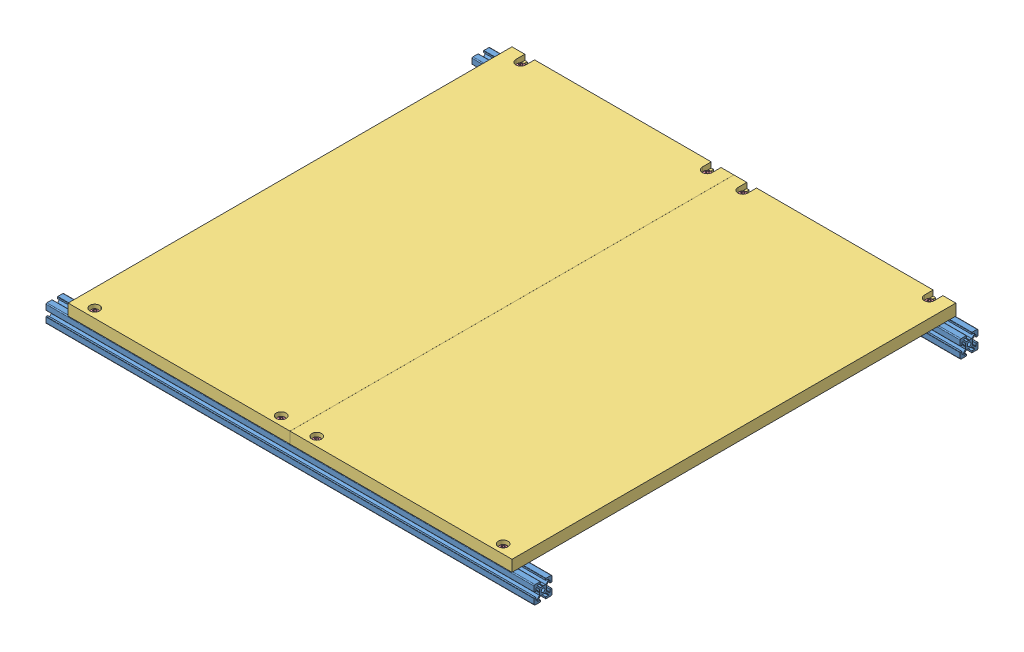
SolidWorks assembly S2_Work_Area_500, configuration Default. Lengths in mm.
Overall size (550 32.7 500).
29 component instances, 5 part files, 65 mates.
Components (placement in the parent):
- 26049-01_550-1: 26049-01_550 [Default] at (-284.2078 -90.7646 -9.7589) x (0 0 1) z (-1 0 0) size (20 20 550)
- 26049-01_550-2: 26049-01_550 [Default] at (-284.2078 -90.7646 -489.7589) x (0 0 1) z (-1 0 0) size (20 20 550)
- 26016-01-1: 26016-01 [Default] at (670.7922 -82.7646 -9.7589) x (0 0 -1) z (-1 0 0) size (10 1.6 15)
- 26016-01-2: 26016-01 [Default] at (670.7922 -82.7646 -489.7589) x (0 0 -1) z (-1 0 0) size (10 1.6 15)
- 26016-01-3: 26016-01 [Default] at (460.7922 -82.7646 -9.7589) x (0 0 -1) z (-1 0 0) size (10 1.6 15)
- 26016-01-4: 26016-01 [Default] at (460.7922 -82.7646 -489.7589) x (0 0 -1) z (-1 0 0) size (10 1.6 15)
- 26016-01-6: 26016-01 [Default] at (420.7422 -82.7646 -489.7589) x (0 0 -1) z (-1 0 0) size (10 1.6 15)
- 26016-01-5: 26016-01 [Default] at (420.7422 -82.7646 -9.7589) x (0 0 -1) z (-1 0 0) size (10 1.6 15)
- 26016-01-7: 26016-01 [Default] at (210.7422 -82.7646 -9.7589) x (0 0 -1) z (-1 0 0) size (10 1.6 15)
- 26016-01-8: 26016-01 [Default] at (210.7422 -82.7646 -489.7589) x (0 0 -1) z (-1 0 0) size (10 1.6 15)
- two_part_wastebaord_500-1: two_part_wastebaord_500 [Default] at (315.7422 -80.7646 -249.7589) x (1 0 0) z (0 1 0) size (250 500 12.7)
- two_part_wastebaord_500-2: two_part_wastebaord_500 [Default] at (565.7922 -80.7646 -249.7589) x (1 0 0) z (0 1 0) size (250 500 12.7)
- 25286-02-1: 25286-02 [Default] at (670.7922 -85.1646 -9.7589) x (0.431918 0 -0.901913) z (0 -1 0) size (9.5 9.5 14.91)
- 25287-02-1: 25287-02 [Default] at (670.7922 -74.0646 -9.7589) x (0.969299 0 -0.245884) z (0 -1 0) size (10 10 0.9)
- 25286-02-2: 25286-02 [Default] at (670.7922 -85.1646 -489.7589) x (1 0 0) z (0 -1 0) size (9.5 9.5 14.91)
- 25287-02-2: 25287-02 [Default] at (670.7922 -73.1646 -489.7589) x (1 0 0) z (0 1 0) size (10 10 0.9)
- 25286-02-3: 25286-02 [Default] at (460.7922 -85.1646 -9.7589) x (1 0 0) z (0 -1 0) size (9.5 9.5 14.91)
- 25287-02-3: 25287-02 [Default] at (460.7922 -73.1646 -9.7589) x (-1 0 0) z (0 1 0) size (10 10 0.9)
- 25286-02-4: 25286-02 [Default] at (460.7922 -85.1646 -489.7589) x (1 0 0) z (0 -1 0) size (9.5 9.5 14.91)
- 25287-02-4: 25287-02 [Default] at (460.7922 -73.1646 -489.7589) x (1 0 0) z (0 1 0) size (10 10 0.9)
- 25286-02-5: 25286-02 [Default] at (420.7422 -85.1646 -9.7589) x (1 0 0) z (0 -1 0) size (9.5 9.5 14.91)
- 25287-02-5: 25287-02 [Default] at (420.7422 -74.0646 -9.7589) x (0.837169 0 0.546944) z (0 -1 0) size (10 10 0.9)
- 25286-02-6: 25286-02 [Default] at (420.7422 -85.1646 -489.7589) x (1 0 0) z (0 -1 0) size (9.5 9.5 14.91)
- 25287-02-6: 25287-02 [Default] at (420.7422 -73.1646 -489.7589) x (1 0 0) z (0 1 0) size (10 10 0.9)
- 25286-02-7: 25286-02 [Default] at (210.7422 -85.1646 -9.7589) x (1 0 0) z (0 -1 0) size (9.5 9.5 14.91)
- 25287-02-7: 25287-02 [Default] at (210.7422 -73.1646 -9.7589) x (0.99999 0 -0.004532) z (0 1 0) size (10 10 0.9)
- 25286-02-8: 25286-02 [Default] at (210.7422 -85.1646 -489.7589) x (1 0 0) z (0 -1 0) size (9.5 9.5 14.91)
- 25287-02-8: 25287-02 [Default] at (210.7422 -73.1646 -489.7589) x (1 0 0) z (0 1 0) size (10 10 0.9)
- 25286-02-9: 25286-02 [Default] at (355.5212 -66.0869 -9.4798) x (1 0 0) z (0 -1 0) size (9.5 9.5 14.91) (suppressed, hidden)
Mates (geometry in assembly coordinates):
- Coincident1: coincident aligned: plane of 26049-01_550-1 through (-284.2078 -80.7646 -13.0589) normal (0 1 0); plane of 26049-01_550-2 through (-284.2078 -80.7646 -480.7589) normal (0 1 0)
- Coincident3: coincident aligned: plane of 26049-01_550-1 through (-284.2078 -90.7646 -9.7589) normal (-1 0 0); plane of 26049-01_550-2 through (-284.2078 -90.7646 -489.7589) normal (-1 0 0)
- Coincident4: coincident anti-aligned: plane of 26049-01_550-1 through (-284.2078 -80.7646 -0.7589) normal (0 1 0); plane of two_part_wastebaord_500-1 through (315.7422 -80.7646 -249.7589) normal (0 -1 0)
- Coincident6: coincident anti-aligned: plane of 26049-01_550-2 through (-284.2078 -82.7646 -486.7589) normal (0 -1 0); plane of 26016-01-8 through (210.7422 -82.7646 -489.7589) normal (0 1 0)
- Coincident7: coincident anti-aligned: plane of 26049-01_550-1 through (-284.2078 -90.7646 -9.7589) normal (0 0 1); plane of 26016-01-7
- Coincident8: coincident anti-aligned: plane of 26049-01_550-1 through (-284.2078 -82.7646 -6.7589) normal (0 -1 0); plane of 26016-01-7 through (210.7422 -82.7646 -9.7589) normal (0 1 0)
- Coincident9: coincident anti-aligned: plane of 26049-01_550-1 through (-284.2078 -82.7646 -6.7589) normal (0 -1 0); plane of 26016-01-5 through (420.7422 -82.7646 -9.7589) normal (0 1 0)
- Coincident10: coincident anti-aligned: plane of 26049-01_550-1 through (-284.2078 -82.7646 -6.7589) normal (0 -1 0); plane of 26016-01-3 through (460.7922 -82.7646 -9.7589) normal (0 1 0)
- Coincident11: coincident anti-aligned: plane of 26049-01_550-1 through (-284.2078 -82.7646 -6.7589) normal (0 -1 0); plane of 26016-01-1 through (670.7922 -82.7646 -9.7589) normal (0 1 0)
- Coincident12: coincident anti-aligned: plane of 26049-01_550-2 through (-284.2078 -82.7646 -486.7589) normal (0 -1 0); plane of 26016-01-8 through (210.7422 -82.7646 -489.7589) normal (0 1 0)
- Coincident13: coincident anti-aligned: plane of 26049-01_550-2 through (-284.2078 -82.7646 -486.7589) normal (0 -1 0); plane of 26016-01-6 through (420.7422 -82.7646 -489.7589) normal (0 1 0)
- Coincident14: coincident anti-aligned: plane of 26049-01_550-2 through (-284.2078 -82.7646 -486.7589) normal (0 -1 0); plane of 26016-01-4 through (460.7922 -82.7646 -489.7589) normal (0 1 0)
- Coincident15: coincident anti-aligned: plane of 26049-01_550-2 through (-284.2078 -82.7646 -486.7589) normal (0 -1 0); plane of 26016-01-2 through (670.7922 -82.7646 -489.7589) normal (0 1 0)
- Coincident16: coincident anti-aligned: plane of 26049-01_550-2 through (-284.2078 -90.7646 -489.7589) normal (0 0 1); plane of 26016-01-2
- Coincident17: coincident anti-aligned: plane of 26049-01_550-2 through (-284.2078 -90.7646 -489.7589) normal (0 0 1); plane of 26016-01-4
- Coincident18: coincident anti-aligned: plane of 26049-01_550-2 through (-284.2078 -90.7646 -489.7589) normal (0 0 1); plane of 26016-01-6
- Coincident19: coincident anti-aligned: plane of 26049-01_550-2 through (-284.2078 -90.7646 -489.7589) normal (0 0 1); plane of 26016-01-8
- Coincident20: coincident anti-aligned: plane of 26049-01_550-2 through (-284.2078 -80.7646 -493.0589) normal (0 1 0); plane of two_part_wastebaord_500-1 through (315.7422 -80.7646 -249.7589) normal (0 -1 0)
- Concentric1: concentric: cylinder of 26016-01-8 through (210.7422 -82.7646 -489.7589) axis (0 -1 0) radius 2.5; cylinder of two_part_wastebaord_500-1 through (210.7422 -627.2258 -489.7589) axis (0 1 0) radius 2.75
- Concentric2: concentric: cylinder of 26016-01-6 through (420.7422 -82.7646 -489.7589) axis (0 -1 0) radius 2.5; cylinder of two_part_wastebaord_500-1 through (420.7422 -627.2258 -489.7589) axis (0 1 0) radius 2.75
- Concentric3: concentric: cylinder of 26016-01-4 through (460.7922 -82.7646 -489.7589) axis (0 -1 0) radius 2.5; cylinder of two_part_wastebaord_500-2 through (460.7922 -627.2258 -489.7589) axis (0 1 0) radius 2.75
- Concentric4: concentric anti-aligned: cylinder of 26016-01-2 through (670.7922 -82.7646 -489.7589) axis (0 -1 0) radius 2.5; cylinder of two_part_wastebaord_500-2 through (670.7922 -627.2258 -489.7589) axis (0 1 0) radius 2.75
- Concentric6: concentric anti-aligned: cylinder of 26016-01-7 through (210.7422 -82.7646 -9.7589) axis (0 -1 0) radius 2.5; cylinder of two_part_wastebaord_500-1 through (210.7422 -627.2258 -9.7589) axis (0 1 0) radius 2.75
- Concentric7: concentric anti-aligned: cylinder of 26016-01-5 through (420.7422 -82.7646 -9.7589) axis (0 -1 0) radius 2.5; cylinder of two_part_wastebaord_500-1 through (420.7422 -627.2258 -9.7589) axis (0 1 0) radius 2.75
- Concentric8: concentric: cylinder of 26016-01-3 through (460.7922 -82.7646 -9.7589) axis (0 -1 0) radius 2.5; cylinder of two_part_wastebaord_500-2 through (460.7922 -627.2258 -9.7589) axis (0 1 0) radius 2.75
- Concentric9: concentric anti-aligned: cylinder of 26016-01-1 through (670.7922 -82.7646 -9.7589) axis (0 -1 0) radius 2.5; cylinder of two_part_wastebaord_500-2 through (670.7922 -627.2258 -9.7589) axis (0 1 0) radius 2.75
- Distance2: distance = 0.05 mm: plane of two_part_wastebaord_500-1 through (440.7422 -80.7646 0.2411) normal (1 0 0); plane of two_part_wastebaord_500-2 through (440.7922 -80.7646 -499.7589) normal (-1 0 0)
- Concentric10: concentric anti-aligned: cylinder of 26016-01-2 through (670.7922 -82.7646 -489.7589) axis (0 -1 0) radius 2.5; cylinder of 25287-02-2 through (670.7922 -74.0646 -489.7589) axis (0 1 0) radius 2.65
- Coincident22: coincident: plane of two_part_wastebaord_500-2 through (670.7922 -74.0646 -489.7589) normal (0 1 0); plane of 25287-02-2 through (670.7922 -74.0646 -489.7589) normal (0 -1 0)
- Concentric11: concentric anti-aligned: cylinder of 26016-01-4 through (460.7922 -82.7646 -489.7589) axis (0 -1 0) radius 2.5; cylinder of 25287-02-4 through (460.7922 -74.0646 -489.7589) axis (0 1 0) radius 2.65
- Coincident23: coincident anti-aligned: plane of two_part_wastebaord_500-2 through (460.7922 -74.0646 -489.7589) normal (0 1 0); plane of 25287-02-4 through (460.7922 -74.0646 -489.7589) normal (0 -1 0)
- Coincident24: coincident anti-aligned: plane of two_part_wastebaord_500-1 through (420.7422 -74.0646 -489.7589) normal (0 1 0); plane of 25287-02-6 through (420.7422 -74.0646 -489.7589) normal (0 -1 0)
- Concentric12: concentric anti-aligned: cylinder of 26016-01-6 through (420.7422 -82.7646 -489.7589) axis (0 -1 0) radius 2.5; cylinder of 25287-02-6 through (420.7422 -74.0646 -489.7589) axis (0 1 0) radius 2.65
- Coincident25: coincident anti-aligned: plane of two_part_wastebaord_500-1 through (210.7422 -74.0646 -489.7589) normal (0 1 0); plane of 25287-02-8 through (210.7422 -74.0646 -489.7589) normal (0 -1 0)
- Concentric13: concentric anti-aligned: cylinder of 26016-01-8 through (210.7422 -82.7646 -489.7589) axis (0 -1 0) radius 2.5; cylinder of 25287-02-8 through (210.7422 -74.0646 -489.7589) axis (0 1 0) radius 2.65
- Concentric14: concentric anti-aligned: cylinder of 26016-01-7 through (210.7422 -82.7646 -9.7589) axis (0 -1 0) radius 2.5; cylinder of 25287-02-7 through (210.7422 -74.0646 -9.7589) axis (0 1 0) radius 2.65
- Coincident26: coincident anti-aligned: plane of two_part_wastebaord_500-1 through (210.7422 -74.0646 -9.7589) normal (0 1 0); plane of 25287-02-7 through (210.7422 -74.0646 -9.7589) normal (0 -1 0)
- Concentric15: concentric aligned: cylinder of 26016-01-5 through (420.7422 -82.7646 -9.7589) axis (0 -1 0) radius 2.5; cylinder of 25287-02-5 through (420.7422 -73.1646 -9.7589) axis (0 -1 0) radius 2.65
- Coincident27: coincident anti-aligned: plane of two_part_wastebaord_500-1 through (420.7422 -74.0646 -9.7589) normal (0 1 0); plane of 25287-02-5 through (420.7422 -74.0646 -9.7589) normal (0 -1 0)
- Concentric16: concentric anti-aligned: cylinder of 26016-01-3 through (460.7922 -82.7646 -9.7589) axis (0 -1 0) radius 2.5; cylinder of 25287-02-3 through (460.7922 -74.0646 -9.7589) axis (0 1 0) radius 2.65
- Coincident28: coincident anti-aligned: plane of two_part_wastebaord_500-2 through (460.7922 -74.0646 -9.7589) normal (0 1 0); plane of 25287-02-3 through (460.7922 -74.0646 -9.7589) normal (0 -1 0)
- Concentric17: concentric aligned: cylinder of 26016-01-1 through (670.7922 -82.7646 -9.7589) axis (0 -1 0) radius 2.5; cylinder of 25287-02-1 through (670.7922 -73.1646 -9.7589) axis (0 -1 0) radius 2.65
- Coincident29: coincident anti-aligned: plane of two_part_wastebaord_500-2 through (670.7922 -74.0646 -9.7589) normal (0 1 0); plane of 25287-02-1 through (670.7922 -74.0646 -9.7589) normal (0 -1 0)
- Concentric18: concentric aligned: cylinder of 26016-01-2 through (670.7922 -82.7646 -489.7589) axis (0 -1 0) radius 2.5; cylinder of 25286-02-2 through (670.7922 -70.4146 -489.7589) axis (0 -1 0) radius 4.75
- Coincident30: coincident anti-aligned: plane of 25286-02-2 through (670.7922 -73.1646 -489.7589) normal (0 -1 0); plane of 25287-02-2 through (670.7922 -73.1646 -489.7589) normal (0 1 0)
- Concentric19: concentric aligned: cylinder of 26016-01-4 through (460.7922 -82.7646 -489.7589) axis (0 -1 0) radius 2.5; cylinder of 25286-02-4 through (460.7922 -70.4146 -489.7589) axis (0 -1 0) radius 4.75
- Coincident31: coincident anti-aligned: plane of 25286-02-4 through (460.7922 -73.1646 -489.7589) normal (0 -1 0); plane of 25287-02-4 through (460.7922 -73.1646 -489.7589) normal (0 1 0)
- Concentric20: concentric aligned: cylinder of 26016-01-6 through (420.7422 -82.7646 -489.7589) axis (0 -1 0) radius 2.5; cylinder of 25286-02-6 through (420.7422 -70.4146 -489.7589) axis (0 -1 0) radius 4.75
- Coincident32: coincident anti-aligned: plane of 25286-02-6 through (420.7422 -73.1646 -489.7589) normal (0 -1 0); plane of 25287-02-6 through (420.7422 -73.1646 -489.7589) normal (0 1 0)
- Concentric21: concentric aligned: cylinder of 26016-01-8 through (210.7422 -82.7646 -489.7589) axis (0 -1 0) radius 2.5; cylinder of 25286-02-8 through (210.7422 -70.4146 -489.7589) axis (0 -1 0) radius 4.75
- Coincident33: coincident anti-aligned: plane of 25286-02-8 through (210.7422 -73.1646 -489.7589) normal (0 -1 0); plane of 25287-02-8 through (210.7422 -73.1646 -489.7589) normal (0 1 0)
- Concentric22: concentric: cylinder of 26016-01-7 through (210.7422 -82.7646 -9.7589) axis (0 -1 0) radius 2.5; cylinder of 25286-02-7 through (210.7422 -70.4146 -9.7589) axis (0 -1 0) radius 4.75
- Coincident34: coincident anti-aligned: plane of 25286-02-7 through (210.7422 -73.1646 -9.7589) normal (0 -1 0); plane of 25287-02-7 through (210.7422 -73.1646 -9.7589) normal (0 1 0)
- Concentric23: concentric aligned: cylinder of 25286-02-5 through (420.7422 -70.4146 -9.7589) axis (0 -1 0) radius 4.75; cylinder of 25287-02-5 through (420.7422 -73.1646 -9.7589) axis (0 -1 0) radius 2.65
- Coincident35: coincident anti-aligned: plane of 25286-02-5 through (420.7422 -73.1646 -9.7589) normal (0 -1 0); plane of 25287-02-5 through (420.7422 -73.1646 -9.7589) normal (0 1 0)
- Concentric24: concentric aligned: cylinder of 26016-01-3 through (460.7922 -82.7646 -9.7589) axis (0 -1 0) radius 2.5; cylinder of 25286-02-3 through (460.7922 -70.4146 -9.7589) axis (0 -1 0) radius 4.75
- Coincident36: coincident anti-aligned: plane of 25286-02-3 through (460.7922 -73.1646 -9.7589) normal (0 -1 0); plane of 25287-02-3 through (460.7922 -73.1646 -9.7589) normal (0 1 0)
- Concentric25: concentric aligned: cylinder of 26016-01-1 through (670.7922 -82.7646 -9.7589) axis (0 -1 0) radius 2.5; cylinder of 25286-02-1 through (670.7922 -70.4146 -9.7589) axis (0 -1 0) radius 4.75
- Coincident37: coincident anti-aligned: plane of 25286-02-1 through (670.7922 -73.1646 -9.7589) normal (0 -1 0); plane of 25287-02-1 through (670.7922 -73.1646 -9.7589) normal (0 1 0)
- Distance3: distance = 25 mm aligned: plane of two_part_wastebaord_500-2 through (690.7922 -80.7646 0.2411) normal (1 0 0); plane of 26049-01_550-1 through (715.7922 -90.7646 -9.7589) normal (1 0 0)
- Coincident39: coincident anti-aligned: plane of 26049-01_550-1 through (-284.2078 -80.7646 -0.7589) normal (0 1 0); plane of two_part_wastebaord_500-2 through (565.7922 -80.7646 -249.7589) normal (0 -1 0)
- Coincident40: coincident anti-aligned: plane of 26049-01_550-1 through (-284.2078 -80.7646 -0.7589) normal (0 1 0); plane of two_part_wastebaord_500-1 through (315.7422 -80.7646 -249.7589) normal (0 -1 0)
- Coincident41: coincident anti-aligned: plane of 26049-01_550-1 through (-284.2078 -90.7646 -9.7589) normal (0 0 1); plane of 26016-01-1
- Coincident42: coincident anti-aligned: plane of 26049-01_550-1 through (-284.2078 -90.7646 -9.7589) normal (0 0 1); plane of 26016-01-3
- Coincident43: coincident anti-aligned: plane of 26049-01_550-1 through (-284.2078 -90.7646 -9.7589) normal (0 0 1); plane of 26016-01-5
